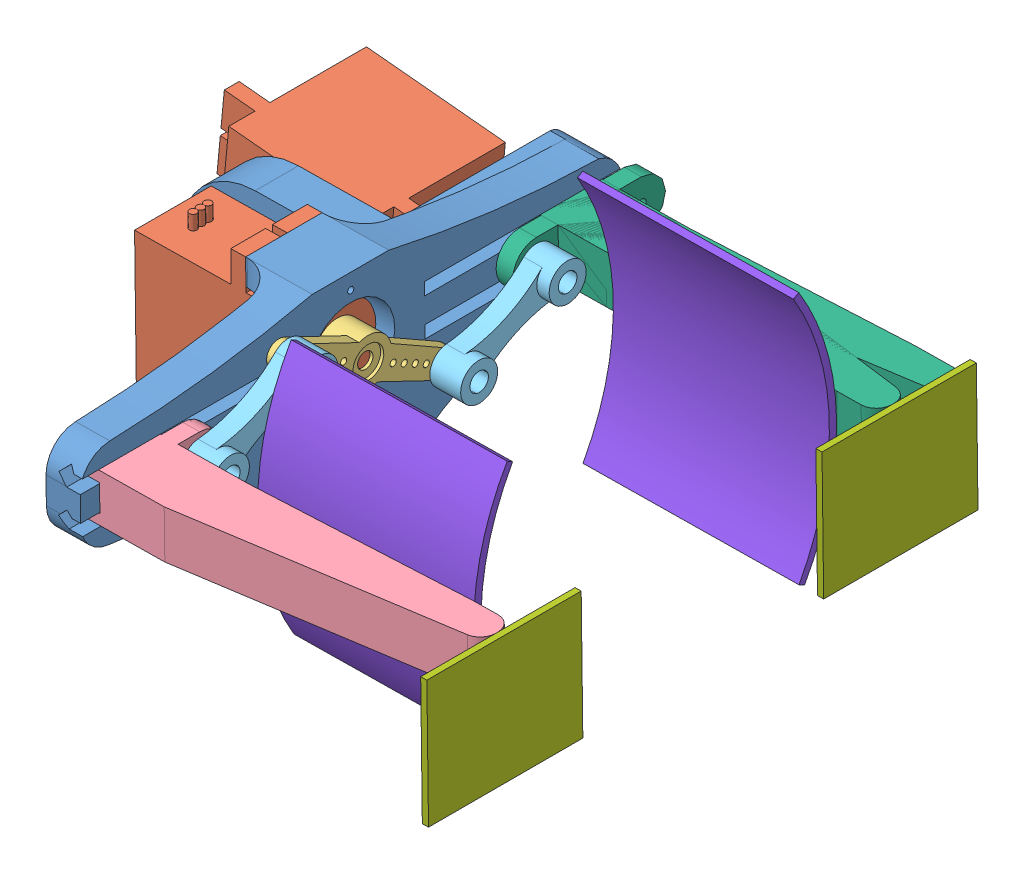
SolidWorks assembly Linear Gripper, configuration Default. Lengths in mm.
Overall size (102.44 43.5 89.01).
13 component instances, 9 part files, 30 mates.
Components (placement in the parent):
- Linear Base-1: Linear Base [Default] x (0.999915 0.013031 0) z (0 0 1) size (35.83 33.39 87.8)
- Servo Micro-2: Servo Micro [Default] at (-5.1496 -0.0624 15.2) x (0.013031 -0.999915 0) z (0 0 1) size (32.6 29.9 12.4)
- Horn-1: Horn [По умолчанию] at (26.3812 5.449 15.2) x (0.006022 -0.462082 -0.886817) z (-0.999915 -0.013031 0) size (32 7.5 5)
- LGrip-1: LGrip [Default] at (23.6565 3.493 50.9779) x (0 0 -1) z (0.999915 0.013031 0) size (17.35 8.47 59.1)
- Linear Link-1: Linear Link [Default] at (29.3373 8.8382 35.2684) x (-0.005492 0.421395 -0.90686) z (-0.011817 0.906783 0.421431) size (21.9 5 6)
- Linear Link-2: Linear Link [Default] at (29.4246 2.138 -4.8684) x (-0.005492 0.421395 -0.90686) z (-0.011817 0.906783 0.421431) size (21.9 5 6)
- LGrip Mirror-1: LGrip Mirror [Default] at (23.6565 3.493 -20.5779) x (0 0 -1) z (0.999915 0.013031 0) size (24.7 8.47 59.1)
- Servo Micro-3: Servo Micro [Default] at (-5.0766 0.4882 -26.6) x (-0.995407 0.095729 0) z (0.095729 0.995407 0) size (32.6 29.9 12.4)
- kicking-1: kicking [Default] at (80.4101 -0.2475 39.6255) x (0 0 1) z (-0.999915 -0.013031 0) size (25 20.5 1)
- kicking-2: kicking [Default] at (80.4101 -0.2475 -24.3889) x (0 0 1) z (-0.999915 -0.013031 0) size (25 20.5 1)
- Part1^Linear Gripper-1: Part1^Linear Gripper [Default] at origin (virtual)
- grabber-2: grabber [Default] at (38.139 -14.4107 38.1415) x (-0.000023 0.001729 0.999999) z (-0.013031 0.999914 -0.001729) size (6.52 35 41)
- grabber-3: grabber [Default] at (37.5225 25.5326 -7.5179) x (-0.000125 0.009559 -0.999954) z (0.01303 -0.999869 -0.00956) size (6.52 35 41)
Mates (geometry in assembly coordinates):
- Parallel1: parallel aligned: plane of Linear Base-1 through (4.3151 0.0562 7) normal (0 0 1); plane of Servo Micro-2 through (17.0012 11.5273 21.4) normal (0 0 1)
- Coincident8: coincident anti-aligned: plane of Linear Base-1 through (12.6864 16.4714 21.4) normal (-0.999915 -0.013031 0); plane of Servo Micro-2 through (12.6864 16.4714 21.4) normal (0.999915 0.013031 0)
- Concentric2: concentric anti-aligned: circle of Servo Micro-2; circle of Horn-1
- Coincident11: coincident anti-aligned: plane of Servo Micro-2 through (21.4481 0.2842 15.2) normal (0.999915 0.013031 0); plane of Horn-1 through (21.3817 5.3838 15.2) normal (-0.999915 -0.013031 0)
- Concentric3: concentric aligned: circle of Linear Base-1; circle of Servo Micro-2
- Coincident12: coincident anti-aligned: plane of Linear Base-1 through (23.698 0.3088 -23) normal (0.999915 0.013031 0); plane of LGrip-1 through (23.6565 3.493 50.9779) normal (-0.999915 -0.013031 0)
- Distance3: distance = 0.15 mm anti-aligned: plane of Linear Base-1 through (-0.1186 9.104 27.1) normal (0.013031 -0.999915 0); plane of LGrip-1 through (23.4313 9.2608 41.7759) normal (-0.013031 0.999915 0)
- Concentric4: concentric anti-aligned: circle of LGrap-1; circle of Linear Link-1
- Concentric5: concentric aligned: circle of Horn-1; circle of Linear Link-1
- Coincident17: coincident anti-aligned: plane of Horn-1 through (26.3812 5.449 15.2) normal (0.999915 0.013031 0); plane of Linear Link-1 through (26.3812 5.449 42.4779) normal (-0.999915 -0.013031 0)
- LimitDistance1: limit distance = 18.8779 mm anti-aligned: plane of LGrip-1 through (28.7319 -2.2595 45.9779) normal (0 0 -1); plane of Linear Base-1 through (0 0 27.1) normal (0 0 1)
- Concentric6: concentric anti-aligned: circle of Horn-1; circle of Linear Link-2
- Coincident20: coincident anti-aligned: plane of Horn-1 through (26.3812 5.449 15.2) normal (0.999915 0.013031 0); plane of Linear Link-2 through (26.4686 -1.2512 2.3412) normal (-0.999915 -0.013031 0)
- Coincident21: coincident anti-aligned: plane of Linear Base-1 through (23.698 0.3088 -23) normal (0.999915 0.013031 0); plane of LGrip Mirror-1 through (23.6565 3.493 -20.5779) normal (-0.999915 -0.013031 0)
- Distance4: distance = 0.15 mm anti-aligned: plane of LGrip Mirror-1 through (23.4313 9.2608 -11.3759) normal (-0.013031 0.999915 0); plane of Linear Base-1 through (-0.1186 9.104 3.3) normal (0.013031 -0.999915 0)
- Concentric7: concentric aligned: circle of Linear Link-2; circle of LGrip Mirror-1
- Concentric8: concentric aligned: cylinder of Linear Base-1 through (0 0 7) axis (0 0 -1) radius 2; cylinder of Servo Micro-3 through (0 0 3.3) axis (0 0 -1) radius 2.5
- Coincident22: coincident anti-aligned: plane of Linear Base-1 through (4.3151 0.0562 0) normal (0 0 -1); plane of Servo Micro-3 through (-5.0766 0.4882 0) normal (0 0 1)
- Coincident23: coincident anti-aligned: plane of LGrip-1 through (80.0539 -49.6617 49.6255) normal (0.999915 0.013031 0); plane of kicking-1 through (79.4101 -0.2605 39.6255) normal (-0.999915 -0.013031 0)
- Coincident24: coincident aligned: plane of LGrip-1 through (23.4313 9.2608 41.7759) normal (-0.013031 0.999915 0); plane of kicking-1 through (79.2766 9.9886 34.6255) normal (-0.013031 0.999915 0)
- Coincident25: coincident: point of LGrip-1; moEndPointRef_w of kicking-1
- Coincident26: coincident anti-aligned: plane of LGrip Mirror-1 through (80.0539 -49.6617 -19.2255) normal (0.999915 0.013031 0); plane of kicking-2 through (79.4101 -0.2605 -24.3889) normal (-0.999915 -0.013031 0)
- Coincident27: coincident aligned: plane of LGrip Mirror-1 through (23.4313 9.2608 -11.3759) normal (-0.013031 0.999915 0); plane of kicking-2 through (79.2766 9.9886 -29.3889) normal (-0.013031 0.999915 0)
- Coincident28: coincident: unknown of LGrip Mirror-1; unknown of kicking-2
- Coincident31: coincident: unknown of LGrip-1; unknown of grabber-2
- Parallel4: parallel anti-aligned: plane of kicking-1 through (79.4101 -0.2605 39.6255) normal (-0.999915 -0.013031 0); plane of grabber-2 through (72.8762 5.9837 3.466) normal (0.999915 0.013031 0)
- Coincident34: coincident: unknown of LGrip Mirror-1; unknown of grabber-3
- Parallel5: parallel anti-aligned: plane of kicking-2 through (79.4101 -0.2605 -24.3889) normal (-0.999915 -0.013031 0); plane of grabber-3 through (72.7844 5.6602 26.9303) normal (0.999915 0.013031 0)
- Distance5: distance = 18.7356 mm: point of grabber-2; point of kicking-1
- Distance6: distance = 18.0429 mm: point of grabber-3; point of kicking-2
